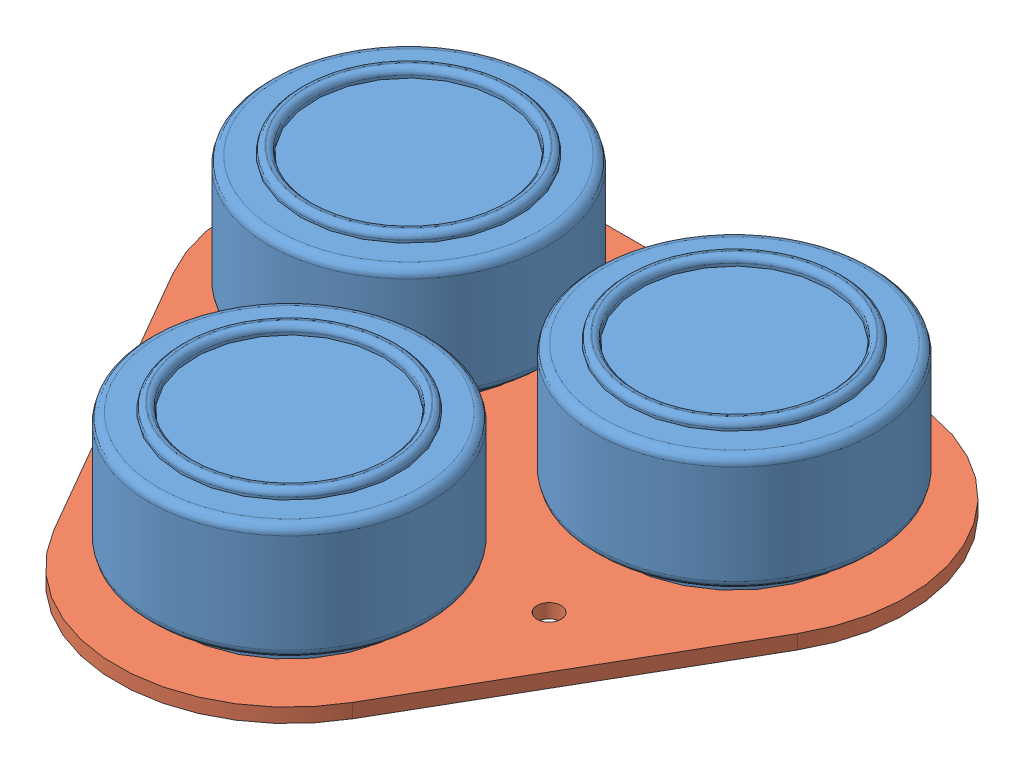
SolidWorks assembly Alphasense, configuration Default. Lengths in mm.
Overall size (77.81 22.15 72.74).
4 component instances, 2 part files, 8 mates.
Components (placement in the parent):
- Alphasense-1: Alphasense [Default] at origin size (32.33 16.5 32.33)
- Alphasense-2: Alphasense [Default] at (37.807 0 0) size (32.33 16.5 32.33)
- Alphasense-3: Alphasense [Default] at (18.9035 0 32.7418) size (32.33 16.5 32.33)
- AlphasenseBoard-1: AlphasenseBoard [Default] at (18.9035 -3.65 10.9139) size (77.81 5.65 72.74)
Mates (geometry in assembly coordinates):
- Parallel1: parallel aligned: plane of Alphasense-1 through (0 13.5 0) normal (0 1 0); plane of Alphasense-2 through (37.807 13.5 0) normal (0 1 0)
- Parallel2: parallel aligned: plane of Alphasense-1 through (0 13.5 0) normal (0 1 0); plane of Alphasense-2 through (37.807 13.5 0) normal (0 1 0)
- Coincident1: coincident aligned: plane of Alphasense-1 through (0 13.5 0) normal (0 1 0); plane of Alphasense-2 through (37.807 13.5 0) normal (0 1 0)
- Coincident2: coincident aligned: plane of Alphasense-1 through (0 13.5 0) normal (0 1 0); plane of Alphasense-3 through (18.9035 13.5 32.7418) normal (0 1 0)
- Coincident4: coincident anti-aligned: plane of Alphasense-1 through (0 -2 0) normal (0 -1 0); plane of AlphasenseBoard-1 through (0 -2 0) normal (0 1 0)
- Concentric1: concentric aligned: cylinder of Alphasense-1 through (0 13.5 0) axis (0 -1 0) radius 16.1655; cylinder of AlphasenseBoard-1 through (0 -2 0) axis (0 -1 0) radius 2
- Concentric2: concentric aligned: cylinder of Alphasense-2 through (37.807 13.5 0) axis (0 -1 0) radius 16.1655; cylinder of AlphasenseBoard-1 through (37.807 -2 0) axis (0 -1 0) radius 2
- Concentric3: concentric aligned: cylinder of Alphasense-3 through (18.9035 13.5 32.7418) axis (0 -1 0) radius 16.1655; cylinder of AlphasenseBoard-1 through (18.9035 -2 32.7418) axis (0 -1 0) radius 2
